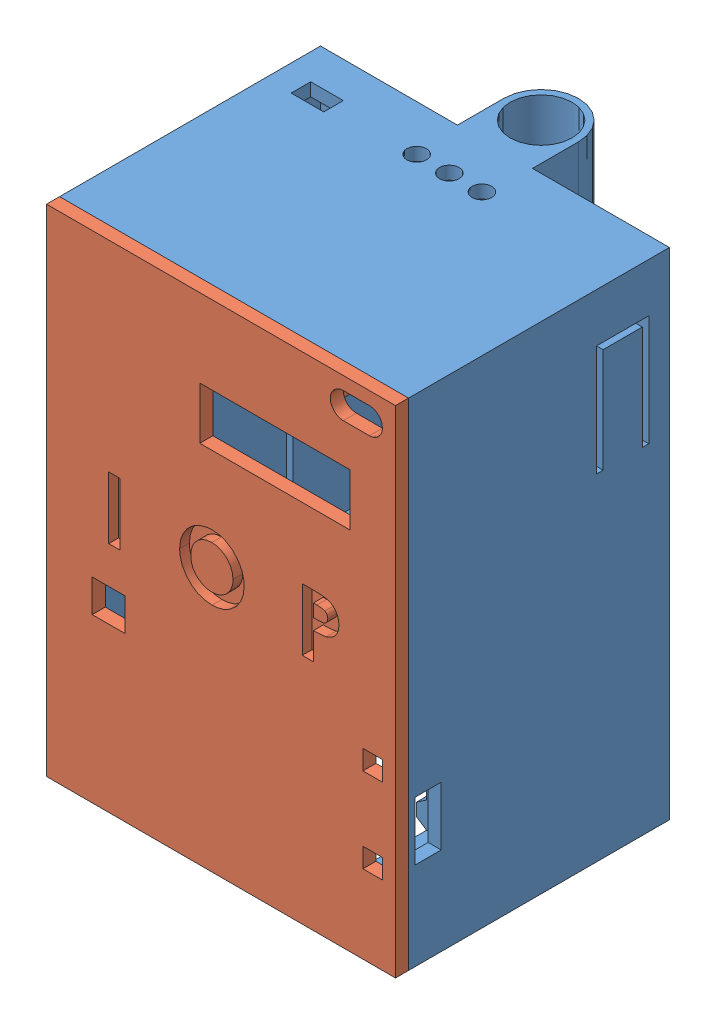
SolidWorks assembly Assem1, configuration Default. Lengths in mm.
Overall size (53.5 76 54.82).
2 component instances, 2 part files, 3 mates.
Components (placement in the parent):
- HPP_Govde_v2-1: HPP_Govde_v2 [Default] at (39.3347 55.1147 42.0508) size (53.5 76 52.82)
- HPP_Kapak_v2-1: HPP_Kapak_v2 [Default] at (46.8793 39.508 84.0508) x (1 0 0) z (0 0 -1) size (53.5 76 10)
Mates (geometry in assembly coordinates):
- Coincident1: coincident anti-aligned: plane of HPP_Govde_v2-1 through (39.3347 55.1147 82.0508) normal (0 0 1); plane of HPP_Kapak_v2-1 through (46.8793 39.508 82.0508) normal (0 0 -1)
- Coincident4: coincident anti-aligned: plane of HPP_Govde_v2-1 through (39.3347 9.6005 82.0508) normal (0 1 0); plane of HPP_Kapak_v2-1 through (46.8793 9.6005 74.0508) normal (0 -1 0)
- Coincident5: coincident aligned: plane of HPP_Govde_v2-1 through (45.9535 55.1147 82.0508) normal (1 0 0); plane of HPP_Kapak_v2-1 through (45.9535 7.6005 82.0508) normal (1 0 0)
